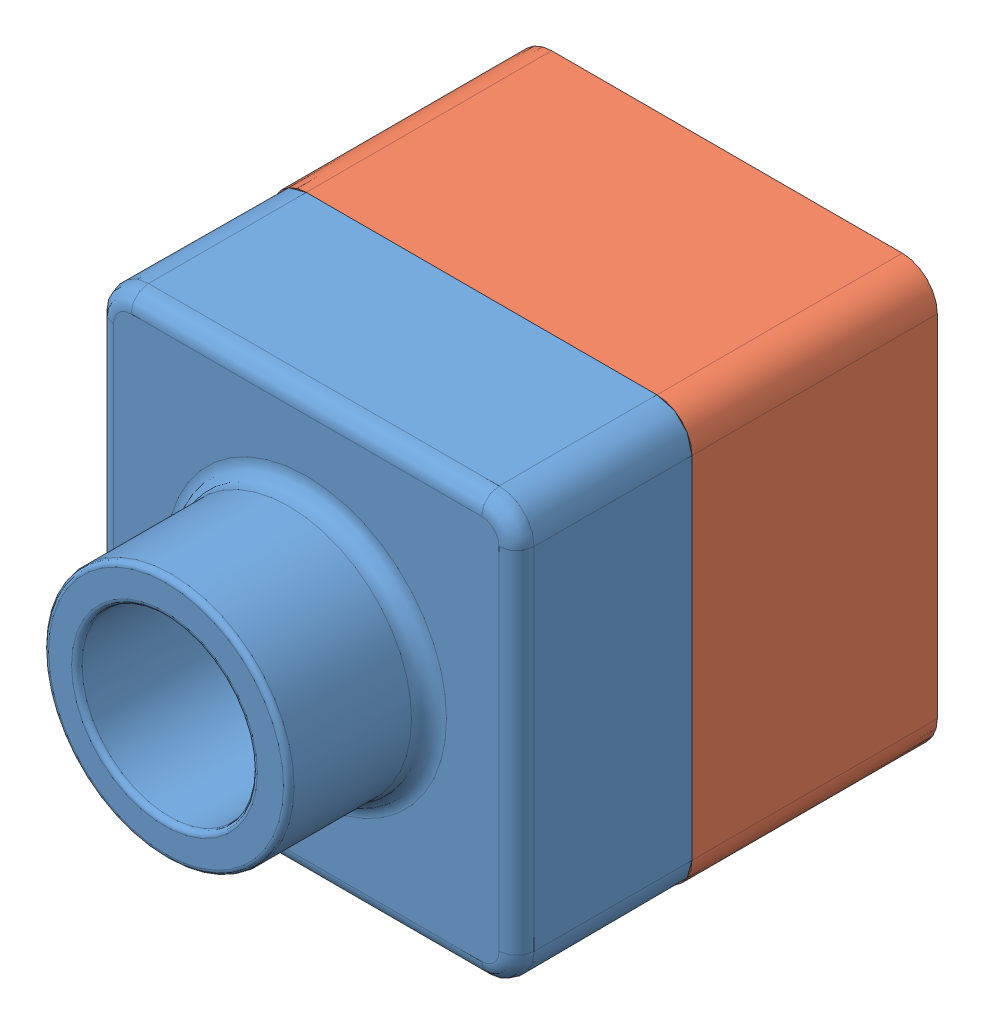
SolidWorks assembly Tutor, configuration Default. Lengths in mm.
Overall size (120 120 160).
2 component instances, 2 part files, 3 mates.
Components (placement in the parent):
- Tutor1-1: Tutor1 [Default] at (-34.9694 75.9368 125.1542) size (120 120 90)
- Tutuor2-1: Tutuor2 [Default] at (-34.9694 75.9368 55.1542) size (120 120 90)
Mates (geometry in assembly coordinates):
- Coincident1: coincident: moEndPointRef_w of Tutor1-1; line of Tutuor2-1 through (75.0306 195.9368 125.1542) axis (-1 0 0)
- Coincident5: coincident aligned: plane of Tutor1-1 through (-34.9694 195.9368 175.1542) normal (0 1 0); plane of Tutuor2-1 through (-34.9694 195.9368 145.1542) normal (0 1 0)
- Coincident7: coincident aligned: plane of Tutor1-1 through (85.0306 75.9368 175.1542) normal (1 0 0); plane of Tutuor2-1 through (85.0306 75.9368 145.1542) normal (1 0 0)
